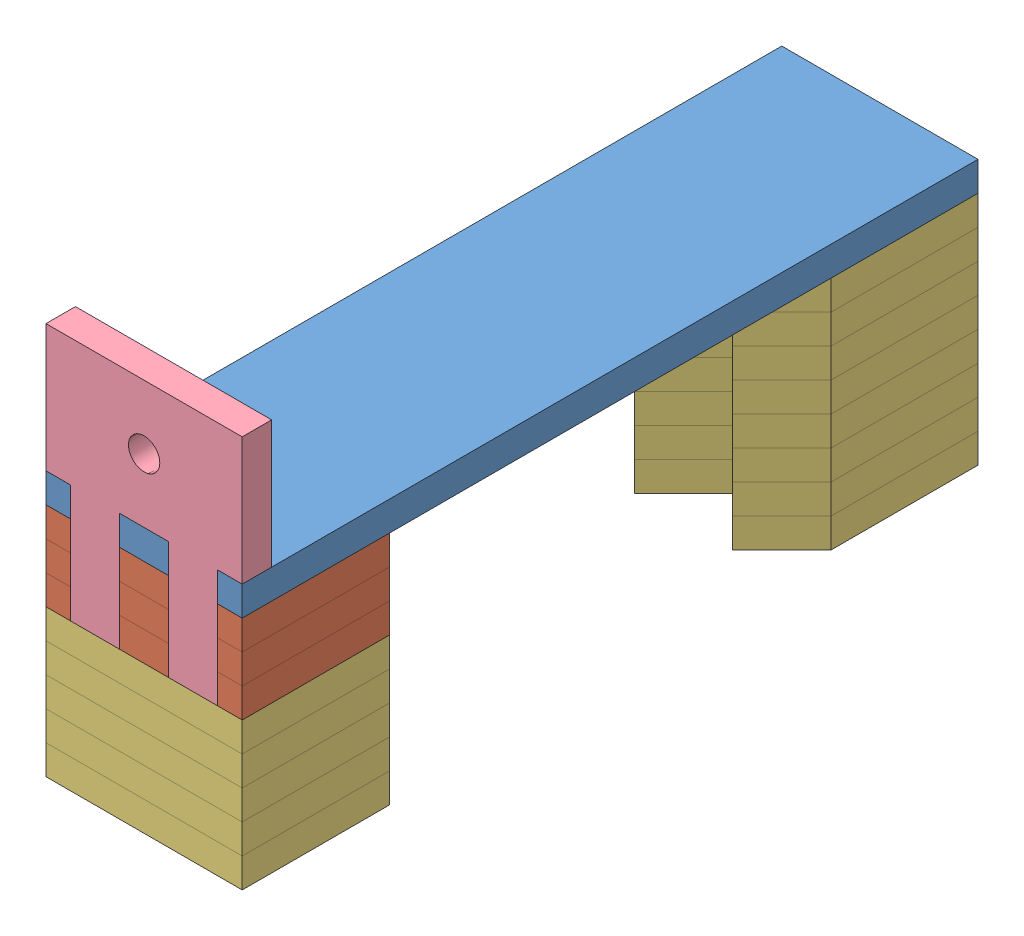
SolidWorks assembly piston, configuration Default. Lengths in mm.
Overall size (20 40 75).
18 component instances, 4 part files, 51 mates.
Components (placement in the parent):
- tooth-strip-1: tooth-strip [Default] at (26.7289 41.9083 55.3369) size (20 3 75)
- tooth-piston-1: tooth-piston [Default] at (26.7289 35.9083 82.8369) x (-1 0 0) z (0 0 -1) size (20 3 20)
- tooth-piston-2: tooth-piston [Default] at (26.7289 38.9083 82.8369) x (-1 0 0) z (0 0 -1) size (20 3 20)
- tooth-end-1: tooth-end [Default] at (26.7289 38.9083 27.8369) size (20 3 20)
- tooth-end-2: tooth-end [Default] at (26.7289 35.9083 27.8369) size (20 3 20)
- tooth-piston-3: tooth-piston [Default] at (26.7289 32.9083 82.8369) x (-1 0 0) z (0 0 -1) size (20 3 20)
- tooth-end-3: tooth-end [Default] at (26.7289 32.9083 27.8369) size (20 3 20)
- stopper-1: stopper [Default] at (16.7289 32.9083 89.8369) x (1 0 0) z (0 -1 0) size (20 3 25)
- tooth-end-4: tooth-end [Default] at (26.7289 29.9083 27.8369) size (20 3 20)
- tooth-end-5: tooth-end [Default] at (26.7289 29.9083 82.8369) x (-1 0 0) z (0 0 -1) size (20 3 20)
- tooth-end-6: tooth-end [Default] at (26.7289 26.9083 27.8369) size (20 3 20)
- tooth-end-7: tooth-end [Default] at (26.7289 23.9083 27.8369) size (20 3 20)
- tooth-end-8: tooth-end [Default] at (26.7289 26.9083 82.8369) x (-1 0 0) z (0 0 -1) size (20 3 20)
- tooth-end-9: tooth-end [Default] at (26.7289 23.9083 82.8369) x (-1 0 0) z (0 0 -1) size (20 3 20)
- tooth-end-10: tooth-end [Default] at (26.7289 20.9083 27.8369) size (20 3 20)
- tooth-end-11: tooth-end [Default] at (26.7289 17.9083 27.8369) size (20 3 20)
- tooth-end-12: tooth-end [Default] at (26.7289 20.9083 82.8369) x (-1 0 0) z (0 0 -1) size (20 3 20)
- tooth-end-13: tooth-end [Default] at (26.7289 17.9083 82.8369) x (-1 0 0) z (0 0 -1) size (20 3 20)
Mates (geometry in assembly coordinates):
- Coincident1: coincident anti-aligned: plane of tooth-strip-1 through (26.7289 41.9083 55.3369) normal (0 -1 0); plane of tooth-piston-2 through (26.7289 41.9083 82.8369) normal (0 1 0)
- Coincident2: coincident aligned: plane of tooth-strip-1 through (36.7289 44.9083 92.8369) normal (1 0 0); plane of tooth-piston-2 through (36.7289 41.9083 72.8369) normal (1 0 0)
- Coincident3: coincident aligned: plane of tooth-strip-1 through (16.7289 44.9083 92.8369) normal (0 0 1); plane of tooth-piston-2 through (36.7289 41.9083 92.8369) normal (0 0 1)
- Coincident4: coincident anti-aligned: plane of tooth-piston-1 through (26.7289 38.9083 82.8369) normal (0 1 0); plane of tooth-piston-2 through (26.7289 38.9083 82.8369) normal (0 -1 0)
- Coincident5: coincident aligned: plane of tooth-piston-1 through (36.7289 38.9083 72.8369) normal (1 0 0); plane of tooth-piston-2 through (36.7289 41.9083 72.8369) normal (1 0 0)
- Coincident6: coincident aligned: plane of tooth-piston-1 through (36.7289 38.9083 92.8369) normal (0 0 1); plane of tooth-piston-2 through (36.7289 41.9083 92.8369) normal (0 0 1)
- Coincident7: coincident anti-aligned: plane of tooth-strip-1 through (26.7289 41.9083 55.3369) normal (0 -1 0); plane of tooth-end-1 through (26.7289 41.9083 27.8369) normal (0 1 0)
- Coincident8: coincident aligned: plane of tooth-strip-1 through (16.7289 44.9083 17.8369) normal (0 0 -1); plane of tooth-end-1 through (16.7289 41.9083 17.8369) normal (0 0 -1)
- Coincident9: coincident aligned: plane of tooth-strip-1 through (36.7289 44.9083 92.8369) normal (1 0 0); plane of tooth-end-1 through (36.7289 41.9083 37.8369) normal (1 0 0)
- Coincident10: coincident anti-aligned: plane of tooth-end-1 through (26.7289 38.9083 27.8369) normal (0 -1 0); plane of tooth-end-2 through (26.7289 38.9083 27.8369) normal (0 1 0)
- Coincident11: coincident aligned: plane of tooth-end-1 through (36.7289 41.9083 37.8369) normal (1 0 0); plane of tooth-end-2 through (36.7289 38.9083 37.8369) normal (1 0 0)
- Coincident12: coincident aligned: plane of tooth-end-1 through (16.7289 41.9083 17.8369) normal (0 0 -1); plane of tooth-end-2 through (16.7289 38.9083 17.8369) normal (0 0 -1)
- Coincident17: coincident anti-aligned: plane of tooth-piston-1 through (26.7289 35.9083 82.8369) normal (0 -1 0); plane of tooth-piston-3 through (26.7289 35.9083 82.8369) normal (0 1 0)
- Coincident18: coincident aligned: plane of tooth-piston-1 through (36.7289 38.9083 72.8369) normal (1 0 0); plane of tooth-piston-3 through (36.7289 35.9083 72.8369) normal (1 0 0)
- Coincident19: coincident aligned: plane of tooth-piston-1 through (36.7289 38.9083 92.8369) normal (0 0 1); plane of tooth-piston-3 through (36.7289 35.9083 92.8369) normal (0 0 1)
- Coincident20: coincident anti-aligned: plane of tooth-end-2 through (26.7289 35.9083 27.8369) normal (0 -1 0); plane of tooth-end-3 through (26.7289 35.9083 27.8369) normal (0 1 0)
- Coincident21: coincident aligned: plane of tooth-end-2 through (36.7289 38.9083 37.8369) normal (1 0 0); plane of tooth-end-3 through (36.7289 35.9083 37.8369) normal (1 0 0)
- Coincident22: coincident aligned: plane of tooth-end-2 through (16.7289 38.9083 17.8369) normal (0 0 -1); plane of tooth-end-3 through (16.7289 35.9083 17.8369) normal (0 0 -1)
- Coincident23: coincident anti-aligned: plane of tooth-strip-1 through (29.2289 44.9083 89.8369) normal (0 0 1); plane of stopper-1 through (16.7289 32.9083 89.8369) normal (0 0 -1)
- Coincident25: coincident anti-aligned: plane of tooth-strip-1 through (26.7289 44.9083 55.3369) normal (0 1 0); plane of stopper-1 through (29.2289 44.9083 89.8369) normal (0 -1 0)
- Coincident26: coincident anti-aligned: plane of tooth-piston-1 through (34.2289 35.9083 92.8369) normal (-1 0 0); plane of stopper-1 through (34.2289 44.9083 89.8359) normal (1 0 0)
- Coincident27: coincident anti-aligned: plane of tooth-piston-3 through (26.7289 32.9083 82.8369) normal (0 -1 0); plane of tooth-end-5 through (26.7289 32.9083 82.8369) normal (0 1 0)
- Coincident28: coincident aligned: plane of tooth-piston-3 through (36.7289 35.9083 72.8369) normal (1 0 0); plane of tooth-end-5 through (36.7289 32.9083 72.8369) normal (1 0 0)
- Coincident29: coincident aligned: plane of tooth-piston-3 through (36.7289 35.9083 92.8369) normal (0 0 1); plane of tooth-end-5 through (36.7289 32.9083 92.8369) normal (0 0 1)
- Coincident30: coincident anti-aligned: plane of tooth-end-3 through (26.7289 32.9083 27.8369) normal (0 -1 0); plane of tooth-end-4 through (26.7289 32.9083 27.8369) normal (0 1 0)
- Coincident31: coincident aligned: plane of tooth-end-3 through (16.7289 35.9083 17.8369) normal (0 0 -1); plane of tooth-end-4 through (16.7289 32.9083 17.8369) normal (0 0 -1)
- Coincident32: coincident aligned: plane of tooth-end-3 through (34.2289 32.9083 35.3369) normal (0.707107 0 0.707107); plane of tooth-end-4 through (34.2289 29.9083 35.3369) normal (0.707107 0 0.707107)
- Coincident33: coincident anti-aligned: plane of tooth-end-5 through (26.7289 29.9083 82.8369) normal (0 -1 0); plane of tooth-end-8 through (26.7289 29.9083 82.8369) normal (0 1 0)
- Coincident34: coincident aligned: plane of tooth-end-5 through (36.7289 32.9083 92.8369) normal (0 0 1); plane of tooth-end-8 through (36.7289 29.9083 92.8369) normal (0 0 1)
- Coincident35: coincident aligned: plane of tooth-end-5 through (36.7289 32.9083 72.8369) normal (1 0 0); plane of tooth-end-8 through (36.7289 29.9083 72.8369) normal (1 0 0)
- Coincident36: coincident anti-aligned: plane of tooth-end-8 through (26.7289 26.9083 82.8369) normal (0 -1 0); plane of tooth-end-9 through (26.7289 26.9083 82.8369) normal (0 1 0)
- Coincident37: coincident aligned: plane of tooth-end-8 through (36.7289 29.9083 92.8369) normal (0 0 1); plane of tooth-end-9 through (36.7289 26.9083 92.8369) normal (0 0 1)
- Coincident38: coincident aligned: plane of tooth-end-8 through (36.7289 29.9083 72.8369) normal (1 0 0); plane of tooth-end-9 through (36.7289 26.9083 72.8369) normal (1 0 0)
- Coincident39: coincident anti-aligned: plane of tooth-end-4 through (26.7289 29.9083 27.8369) normal (0 -1 0); plane of tooth-end-6 through (26.7289 29.9083 27.8369) normal (0 1 0)
- Coincident40: coincident aligned: plane of tooth-end-4 through (16.7289 32.9083 17.8369) normal (0 0 -1); plane of tooth-end-6 through (16.7289 29.9083 17.8369) normal (0 0 -1)
- Coincident41: coincident aligned: plane of tooth-end-4 through (36.7289 32.9083 37.8369) normal (1 0 0); plane of tooth-end-6 through (36.7289 29.9083 37.8369) normal (1 0 0)
- Coincident42: coincident anti-aligned: plane of tooth-end-6 through (26.7289 26.9083 27.8369) normal (0 -1 0); plane of tooth-end-7 through (26.7289 26.9083 27.8369) normal (0 1 0)
- Coincident43: coincident aligned: plane of tooth-end-6 through (16.7289 29.9083 17.8369) normal (0 0 -1); plane of tooth-end-7 through (16.7289 26.9083 17.8369) normal (0 0 -1)
- Coincident44: coincident aligned: plane of tooth-end-6 through (36.7289 29.9083 37.8369) normal (1 0 0); plane of tooth-end-7 through (36.7289 26.9083 37.8369) normal (1 0 0)
- Coincident45: coincident anti-aligned: plane of tooth-end-9 through (26.7289 23.9083 82.8369) normal (0 -1 0); plane of tooth-end-12 through (26.7289 23.9083 82.8369) normal (0 1 0)
- Coincident46: coincident aligned: plane of tooth-end-9 through (36.7289 26.9083 92.8369) normal (0 0 1); plane of tooth-end-12 through (36.7289 23.9083 92.8369) normal (0 0 1)
- Coincident47: coincident aligned: plane of tooth-end-9 through (36.7289 26.9083 72.8369) normal (1 0 0); plane of tooth-end-12 through (36.7289 23.9083 72.8369) normal (1 0 0)
- Coincident48: coincident anti-aligned: plane of tooth-end-12 through (26.7289 20.9083 82.8369) normal (0 -1 0); plane of tooth-end-13 through (26.7289 20.9083 82.8369) normal (0 1 0)
- Coincident49: coincident aligned: plane of tooth-end-12 through (36.7289 23.9083 92.8369) normal (0 0 1); plane of tooth-end-13 through (36.7289 20.9083 92.8369) normal (0 0 1)
- Coincident50: coincident aligned: plane of tooth-end-12 through (36.7289 23.9083 72.8369) normal (1 0 0); plane of tooth-end-13 through (36.7289 20.9083 72.8369) normal (1 0 0)
- Coincident51: coincident anti-aligned: plane of tooth-end-7 through (26.7289 23.9083 27.8369) normal (0 -1 0); plane of tooth-end-10 through (26.7289 23.9083 27.8369) normal (0 1 0)
- Coincident52: coincident aligned: plane of tooth-end-7 through (16.7289 26.9083 17.8369) normal (0 0 -1); plane of tooth-end-10 through (16.7289 23.9083 17.8369) normal (0 0 -1)
- Coincident53: coincident aligned: plane of tooth-end-7 through (36.7289 26.9083 37.8369) normal (1 0 0); plane of tooth-end-10 through (36.7289 23.9083 37.8369) normal (1 0 0)
- Coincident54: coincident anti-aligned: plane of tooth-end-10 through (26.7289 20.9083 27.8369) normal (0 -1 0); plane of tooth-end-11 through (26.7289 20.9083 27.8369) normal (0 1 0)
- Coincident55: coincident aligned: plane of tooth-end-10 through (36.7289 23.9083 37.8369) normal (1 0 0); plane of tooth-end-11 through (36.7289 20.9083 37.8369) normal (1 0 0)
- Coincident56: coincident aligned: plane of tooth-end-10 through (16.7289 23.9083 17.8369) normal (0 0 -1); plane of tooth-end-11 through (16.7289 20.9083 17.8369) normal (0 0 -1)
